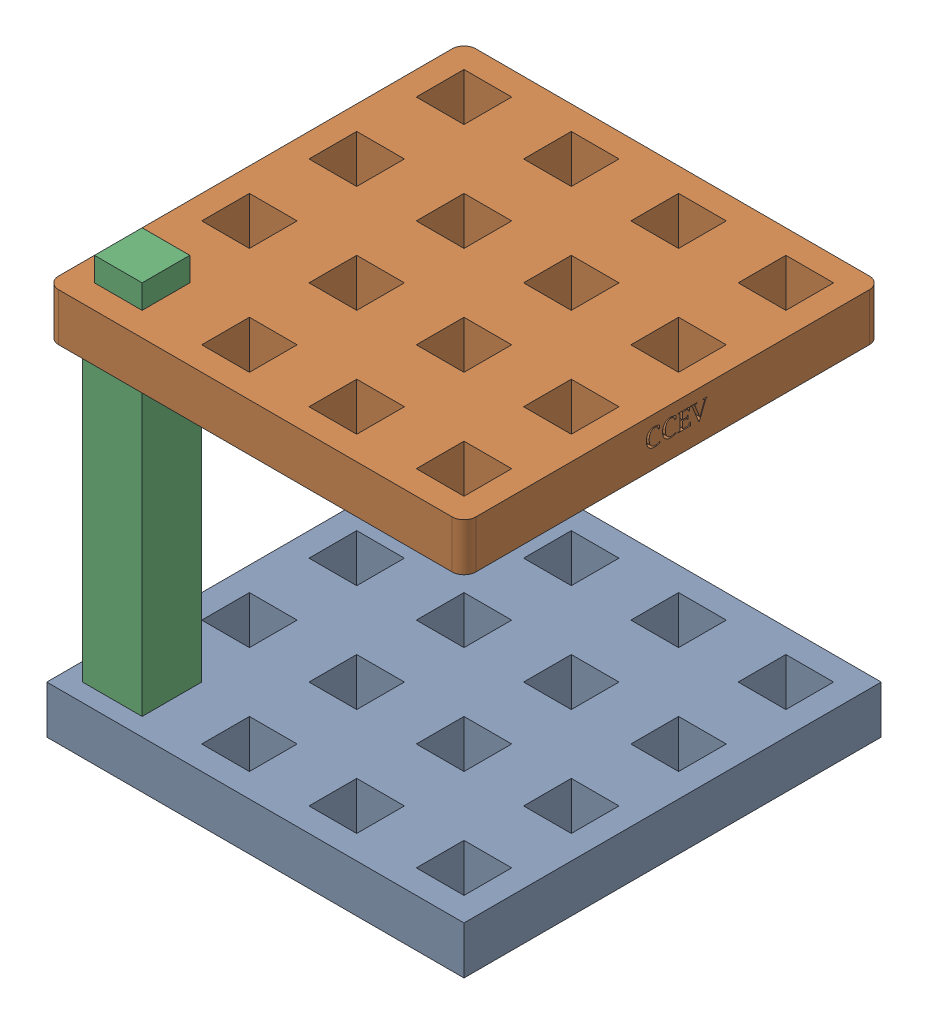
SolidWorks assembly paintholder, configuration Default. Lengths in mm.
Overall size (88.9 88.9 88.9).
3 component instances, 3 part files, 7 mates.
Components (placement in the parent):
- paintbase-1: paintbase [Default] at (-14.1291 21.5539 -3.7364) size (88.9 10.16 88.9)
- paintsup-1: paintsup [Default] at (-14.1291 95.2139 -3.7364) size (88.9 10.16 88.9)
- paintbeam-1: paintbeam [Default] at (-10.3191 95.2139 68.6536) x (0 0 1) z (1 0 0) size (12.7 88.9 12.7)
Mates (geometry in assembly coordinates):
- Coincident12: coincident anti-aligned: plane of paintsup-1 through (-9.0491 102.2551 48.7168) normal (1 0 0); plane of paintbeam-1 through (-9.0491 107.12 47.2543) normal (-1 0 0)
- Coincident13: coincident anti-aligned: plane of paintsup-1 through (-9.0491 102.2551 48.7168) normal (0 0.287901 0.95766); plane of paintbeam-1 through (1.1109 107.12 47.2543) normal (0 -0.287901 -0.95766)
- Coincident14: coincident anti-aligned: plane of paintbase-1 through (1.1109 31.7139 69.9236) normal (-1 0 0); plane of paintbeam-1 through (1.1109 21.984 72.8487) normal (1 0 0)
- Parallel1: parallel: plane of paintsup-1 through (-14.1291 71.3185 -18.8993) normal (0 -0.95766 0.287901); line of paintbeam-1 through (-9.0491 21.984 72.8487) axis (1 0 0)
- Coincident19: coincident aligned: line of paintsup-1 through (-9.0491 95.2139 80.0836) axis (1 0 0); line of paintbeam-1 through (-9.0491 95.2139 80.0836) axis (1 0 0)
- Coincident20: coincident anti-aligned: line of paintbase-1 through (1.1109 31.7139 69.9236) axis (-1 0 0); line of paintbeam-1 through (-9.0491 31.7139 69.9236) axis (1 0 0)
- Coincident21: coincident anti-aligned: line of paintbase-1 through (1.1109 21.5539 80.0836) axis (0 0 -1); line of paintbeam-1 through (1.1109 21.5539 69.9236) axis (0 0 1)
